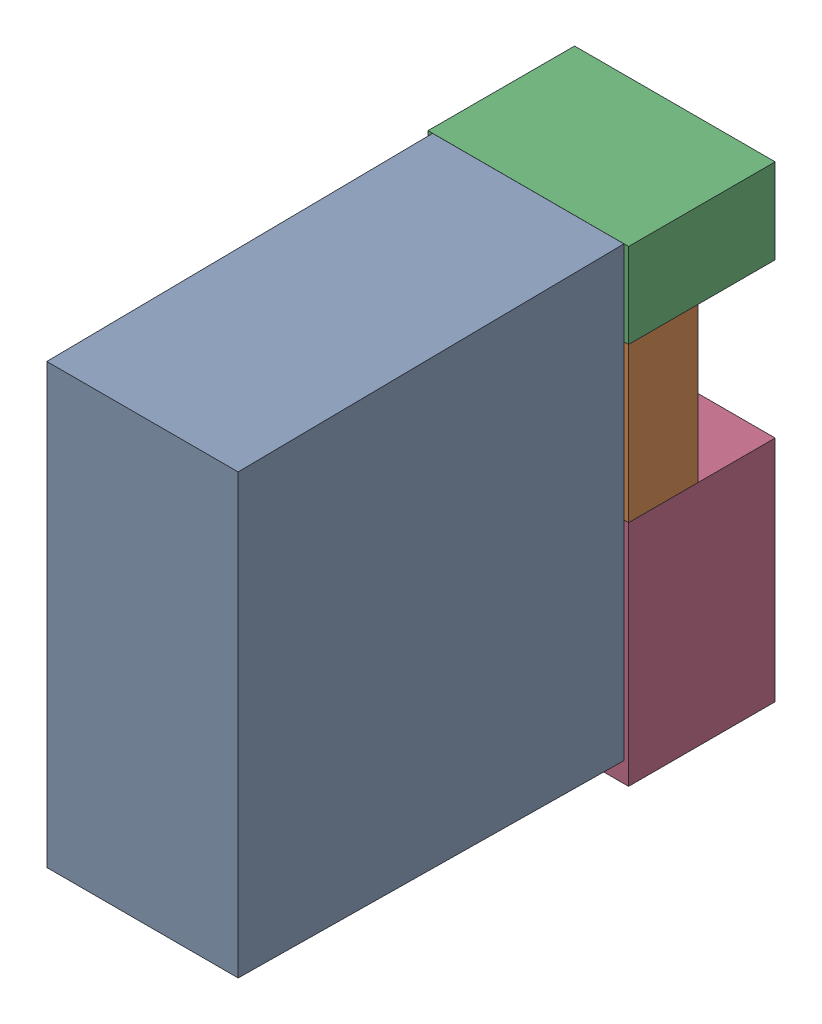
SolidWorks assembly K11, configuration Default. Lengths in mm.
Overall size (13 30.3 34.5).
7 component instances, 4 part files, 0 mates.
Components (placement in the parent):
- relais_40_61_8_006_0000-1: relais_40_61_8_006_0000 [Default] at (159.385 15.7216 9.5) x (0 1 0) z (1 0 0) size (29 30 12.4)
- 1151725064-1: 1151725064 [Default] at (159.385 34.225 5) size (13 10 4.5)
  - Extruded_3-1: Extruded_3 [Default] at origin size (13 10 4.5)
- 1151724928-1: 1151724928 [Default] at (159.385 41.975 0) size (13 5.5 9.5)
  - Extruded_2-1: Extruded_2 [Default] at origin size (13 5.5 9.5)
- 1151724792-1: 1151724792 [Default] at (159.385 21.825 0) size (13 14.8 9.5)
  - Extruded_4-1: Extruded_4 [Default] at origin size (13 14.8 9.5)
